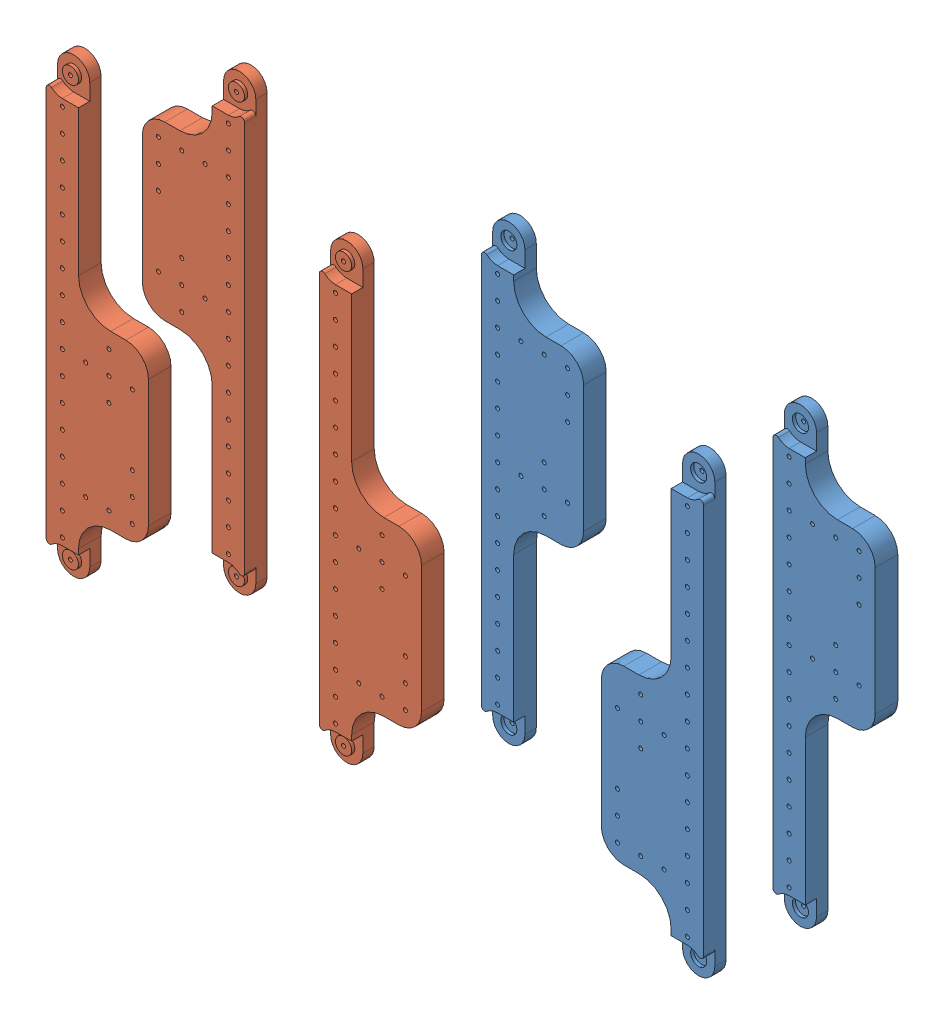
SolidWorks assembly milling_assem, configuration Default. Lengths in mm.
Overall size (1016 508 17.78).
6 component instances, 2 part files, 12 mates.
Components (placement in the parent):
- board_link_female-1: board_link_female [female] at (374.2481 463.7077 -17.78) x (0 1 0) z (1 0 0) size (355.6 17.78 105.83)
- board_link_male-1: board_link_male [male] at (31.75 76.1718 17.78) x (0 -1 0) z (1 0 0) size (355.6 17.78 105.83)
- board_link_male-2: board_link_male [male] at (162.4012 460.3091 17.78) x (0 1 0) z (-1 0 0) size (355.6 17.78 105.83)
- board_link_male-3: board_link_male [male] at (246.6798 56.7789 17.78) x (0 -1 0) z (1 0 0) size (355.6 17.78 105.83)
- board_link_female-2: board_link_female [female] at (603.6864 453.8632 -17.78) x (0 1 0) z (1 0 0) size (355.6 17.78 105.83)
- board_link_female-4: board_link_female [female] at (523.5865 49.9232 -17.78) x (0 -1 0) z (-1 0 0) size (355.6 17.78 105.83)
Mates (geometry in assembly coordinates):
- Coincident1: coincident anti-aligned: plane of board_link_male-1 through (31.75 76.1718 0) normal (0 0 -1)
- Distance1: distance = 19.05 mm: line of assembly; line of assembly; line of board_link_male-1 through (19.05 76.1718 0) axis (0 1 0)
- Coincident3: coincident aligned: plane of board_link_male-1 through (31.75 76.1718 17.78) normal (0 0 1); plane of board_link_male-2 through (162.4012 460.3091 17.78) normal (0 0 1)
- Parallel1: parallel anti-aligned: line of board_link_male-2 through (94.6678 400.1958 17.78) axis (0 -1 0)
- Coincident5: coincident aligned: plane of board_link_female-1 through (374.2481 463.7077 17.78) normal (0 0 1); plane of board_link_male-2 through (162.4012 460.3091 17.78) normal (0 0 1)
- Coincident6: coincident aligned: plane of board_link_male-2 through (162.4012 460.3091 17.78) normal (0 0 1); plane of board_link_male-3 through (246.6798 56.7789 17.78) normal (0 0 1)
- Parallel2: parallel aligned: line of board_link_male-3 through (233.9798 68.1381 17.78) axis (0 1 0)
- Parallel3: parallel anti-aligned: line of board_link_female-1 through (361.5481 452.3484 17.78) axis (0 -1 0)
- Coincident9: coincident aligned: plane of board_link_female-1 through (374.2481 463.7077 17.78) normal (0 0 1); plane of board_link_female-2 through (603.6864 453.8632 17.78) normal (0 0 1)
- Coincident10: coincident aligned: plane of board_link_female-1 through (374.2481 463.7077 17.78) normal (0 0 1); plane of board_link_female-4 through (523.5865 49.9232 17.78) normal (0 0 1)
- Parallel4: parallel aligned: line of board_link_female-4 through (536.2865 61.2824 17.78) axis (0 1 0)
- Parallel5: parallel anti-aligned: line of board_link_female-2 through (590.9864 442.5039 17.78) axis (0 -1 0)
